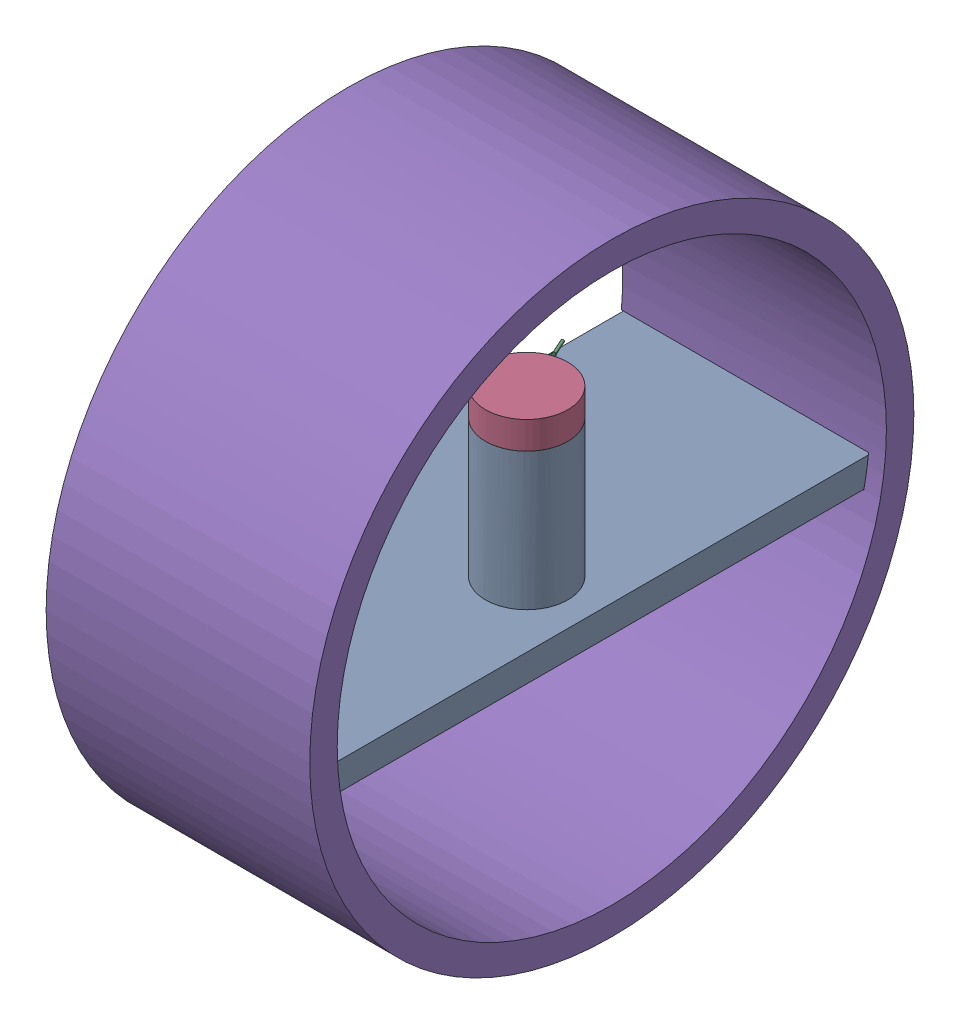
SolidWorks assembly Assem_V2, configuration Default. Lengths in mm.
Overall size (48 110 110).
4 component instances, 4 part files, 9 mates.
Components (placement in the parent):
- Part1_V2-1: Part1_V2 [Default] at (-38.3343 -9.8179 56.3349) size (45 30 105)
- Part4_V2-1: Part4_V2 [Default] at (-5.3343 20.1821 3.8349) x (0.38649 0 0.922294) z (-0.922294 0 0.38649) size (9.8 20 9.8)
- Part3_V2-1: Part3_V2 [Default] at (-5.3343 20.1821 3.8349) x (-0.408 0 -0.912982) z (0.912982 0 -0.408) size (20.5 22.5 15)
- Part2_V2-1: Part2_V2 [Default] at (9.6657 0.5465 3.3349) x (0 0 1) z (-1 0 0) size (110 110 48)
Mates (geometry in assembly coordinates):
- Concentric1: concentric aligned: circle of Part1_V2-1; circle of Part4_V2-1
- Coincident1: coincident anti-aligned: plane of Part1_V2-1 through (-5.3343 0.1821 3.8349) normal (0 1 0); plane of Part4_V2-1 through (-5.3343 0.1821 3.8349) normal (0 -1 0)
- Concentric2: concentric anti-aligned: circle of Part4_V2-1; circle of Part3_V2-1
- Coincident2: coincident anti-aligned: plane of Part4_V2-1 through (-5.3343 20.1821 3.8349) normal (0 1 0); plane of Part3_V2-1 through (-5.3343 20.1821 3.8349) normal (0 -1 0)
- Coincident5: coincident anti-aligned: plane of Part1_V2-1 through (-38.3343 -4.8179 56.3349) normal (0 0 1); plane of Part2_V2-1 through (6.6657 -9.9535 56.3349) normal (0 0 -1)
- Parallel3: parallel anti-aligned: plane of Part1_V2-1 through (-38.3343 -4.8179 -48.6651) normal (0 0 -1); plane of Part2_V2-1 through (6.6657 -9.9535 -49.6651) normal (0 0 1)
- Coincident8: coincident anti-aligned: line of Part1_V2-1 through (6.6657 -4.8179 56.3349) axis (0 -1 0); line of Part2_V2-1 through (6.6657 -9.9535 56.3349) axis (0 1 0)
- Parallel4: parallel aligned: line of Part1_V2-1 through (6.6657 -4.8179 -48.6651) axis (0 -1 0); line of Part2_V2-1 through (6.6657 -4.4535 -49.6651) axis (0 -1 0)
- Coincident10: coincident anti-aligned: plane of Part1_V2-1 through (6.6657 -4.8179 56.3349) normal (1 0 0); plane of Part2_V2-1 through (6.6657 0.5465 3.3349) normal (-1 0 0)
